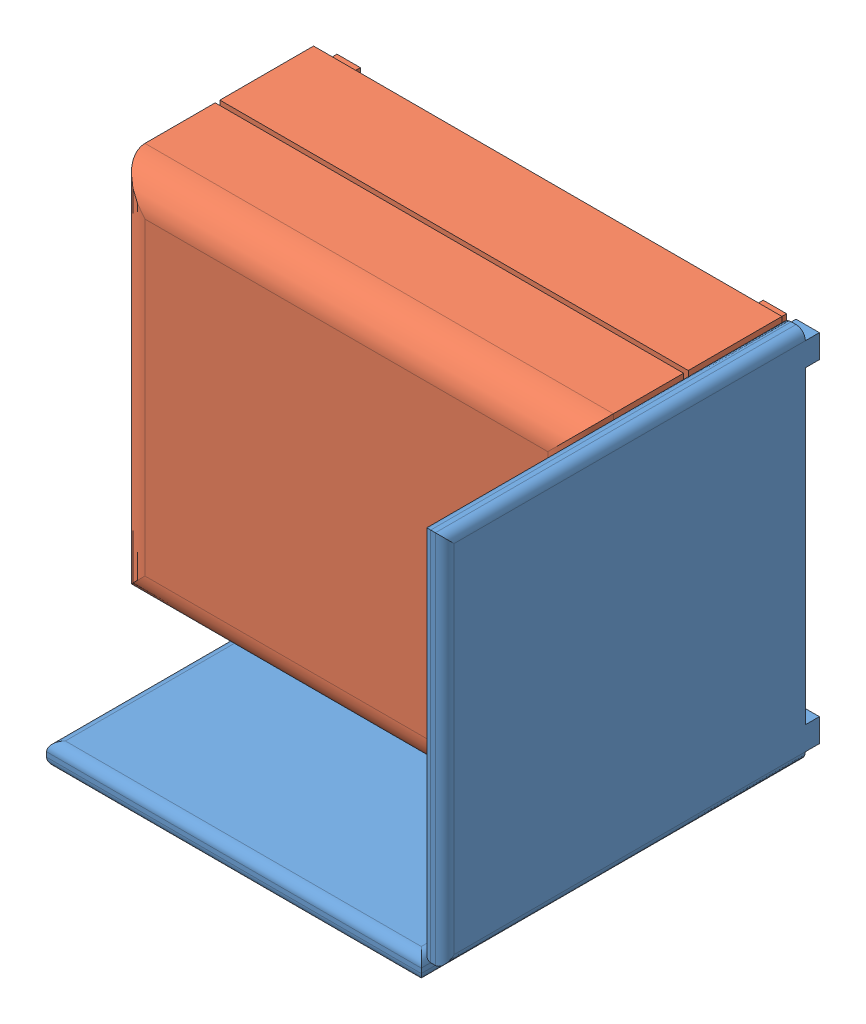
SolidWorks assembly Sofa-L, configuration Standard. Lengths in mm.
Overall size (1050 850 800).
3 component instances, 2 part files, 6 mates.
Components (placement in the parent):
- Rückenstütze-80x80-1: Rückenstütze-80x80 [Standard] at (48.0974 -746.2493 765.6126) size (800 50 800)
- Sitzelement-1: Sitzelement [Standard] at (-51.9026 -321.2493 795.6126) x (0 -1 0) z (-1 0 0) size (800 460 1000)
- Rückenstütze-80x80-3: Rückenstütze-80x80 [Standard] at (473.0974 -321.2493 765.6126) x (0 -1 0) z (0 0 1) size (800 50 800)
Mates (geometry in assembly coordinates):
- Deckungsgleich2: coincident aligned: plane of Rückenstütze-80x80-1 through (48.0974 -746.2493 765.6126) normal (0 0 -1); plane of Sitzelement-1 through (-51.9026 -321.2493 765.6126) normal (0 0 -1)
- Deckungsgleich3: coincident aligned: plane of Rückenstütze-80x80-1 through (448.0974 -771.2493 1565.6126) normal (1 0 0); plane of Sitzelement-1 through (448.0974 78.7507 995.6126) normal (1 0 0)
- Deckungsgleich13: coincident anti-aligned: plane of Rückenstütze-80x80-1 through (-331.9026 -721.2493 795.6126) normal (0 1 0); plane of Sitzelement-1 through (-551.9026 -721.2493 995.6126) normal (0 -1 0)
- Deckungsgleich14: coincident aligned: plane of Sitzelement-1 through (-51.9026 -321.2493 765.6126) normal (0 0 -1); plane of Rückenstütze-80x80-3 through (473.0974 -321.2493 765.6126) normal (0 0 -1)
- Deckungsgleich15: coincident anti-aligned: plane of Sitzelement-1 through (448.0974 78.7507 995.6126) normal (1 0 0); plane of Rückenstütze-80x80-3 through (448.0974 58.7507 795.6126) normal (-1 0 0)
- Deckungsgleich16: coincident aligned: plane of Sitzelement-1 through (-551.9026 -721.2493 995.6126) normal (0 -1 0); plane of Rückenstütze-80x80-3 through (448.0974 -721.2493 1565.6126) normal (0 -1 0)
